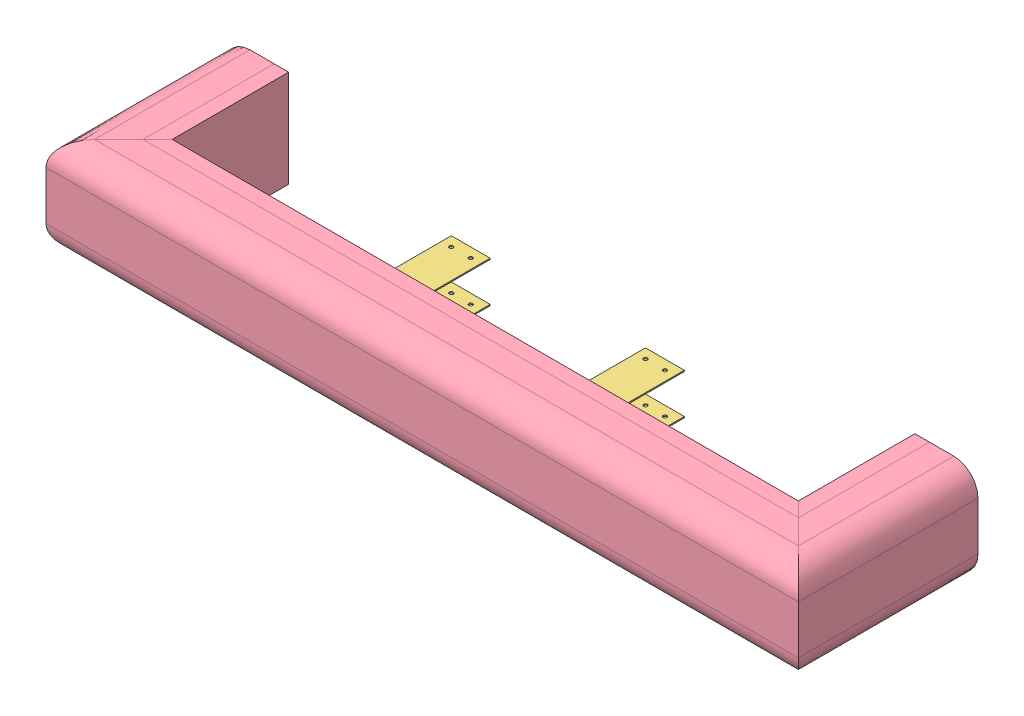
SolidWorks assembly 600-000 Bumper Asm, configuration Default. Lengths in mm.
Overall size (984.25 127 234.95).
6 component instances, 4 part files, 15 mates.
Components (placement in the parent):
- 600-002 BumperPlate-1: 600-002 BumperPlate [Default] at origin size (812.8 50.8 3.17)
- 600-003 BumperPlateCornerMount-1: 600-003 BumperPlateCornerMount [back] at (25.4 0 0) size (25.4 50.8 25.4)
- 600-004 BumperPlateSupport-1: 600-004 BumperPlateSupport [Default] at (254 0 -1.5875) x (0 0 -1) z (1 0 0) size (101.6 53.97 50.8)
- 600-004 BumperPlateSupport-2: 600-004 BumperPlateSupport [Default] at (508 0 -1.5875) x (0 0 -1) z (1 0 0) size (101.6 53.97 50.8)
- 600-003 BumperPlateCornerMount-2: 600-003 BumperPlateCornerMount [front] at (787.4 0 0) x (0 0 -1) z (1 0 0) size (25.4 50.8 25.4)
- 600-001 Bumper-1: 600-001 Bumper [Default] at (406.4 -40.1207 -146.05) size (984.25 127 234.95)
Mates (geometry in assembly coordinates):
- Coincident1: coincident: plane of 600-002 BumperPlate-1 through (0 0 0) normal (0 0 -1); plane of 600-003 BumperPlateCornerMount-2 through (787.4 50.8 0) normal (0 0 1)
- Coincident2: coincident: plane of 600-002 BumperPlate-1 through (0 0 0) normal (0 0 -1); plane of 600-003 BumperPlateCornerMount-1 through (25.4 50.8 0) normal (0 0 1)
- Coincident3: coincident: plane of 600-002 BumperPlate-1 through (0 0 0) normal (0 0 -1); plane of 600-004 BumperPlateSupport-1 through (304.8 -1.5875 0) normal (0 0 1)
- Coincident4: coincident: plane of 600-002 BumperPlate-1 through (0 0 0) normal (0 0 -1); plane of 600-004 BumperPlateSupport-2 through (558.8 -1.5875 0) normal (0 0 1)
- Coincident7: coincident: plane of 600-002 BumperPlate-1 through (0 50.8 3.175) normal (0 1 0); plane of 600-003 BumperPlateCornerMount-1 through (25.4 50.8 0) normal (0 1 0)
- Coincident8: coincident: plane of 600-002 BumperPlate-1 through (0 50.8 3.175) normal (0 1 0); plane of 600-003 BumperPlateCornerMount-2 through (787.4 50.8 0) normal (0 1 0)
- Distance1: distance = 25.4 mm: plane of 600-003 BumperPlateCornerMount-2 through (787.4 50.8 0) normal (1 0 0); plane of 600-002 BumperPlate-1 through (812.8 0 3.175) normal (1 0 0)
- Distance2: distance = 25.4 mm: plane of 600-003 BumperPlateCornerMount-1 through (25.4 50.8 0) normal (-1 0 0); plane of 600-002 BumperPlate-1 through (0 0 3.175) normal (-1 0 0)
- Concentric2: concentric: cylinder of 600-002 BumperPlate-1 through (279.4 25.4 3.175) axis (0 0 -1) radius 3.175; circle of 600-004 BumperPlateSupport-1
- Concentric3: concentric: cylinder of 600-002 BumperPlate-1 through (533.4 25.4 3.175) axis (0 0 -1) radius 3.175; cylinder of 600-004 BumperPlateSupport-2 through (533.4 25.4 0) axis (0 0 -1) radius 3.175
- Parallel1: parallel: line of 600-002 BumperPlate-1 through (812.8 50.8 3.175) axis (-1 0 0); plane of 600-004 BumperPlateSupport-2 through (558.8 52.3875 0) normal (0 1 0)
- Parallel2: parallel: line of 600-002 BumperPlate-1 through (812.8 50.8 3.175) axis (-1 0 0); plane of 600-004 BumperPlateSupport-1 through (304.8 52.3875 0) normal (0 1 0)
- Coincident9: coordinate: point of 600-002 BumperPlate-1; point of assembly
- Distance3: distance = 3.175 mm: plane of 600-001 Bumper-1 through (-94.08 -40.1207 6.35) normal (0 0 -1); plane of 600-002 BumperPlate-1 through (0 0 3.175) normal (0 0 1)
- Distance4: distance = 3.175 mm: plane of 600-002 BumperPlate-1 through (0 0 3.175) normal (-1 0 0); plane of 600-001 Bumper-1 through (-3.175 -40.1207 -146.05) normal (1 0 0)
